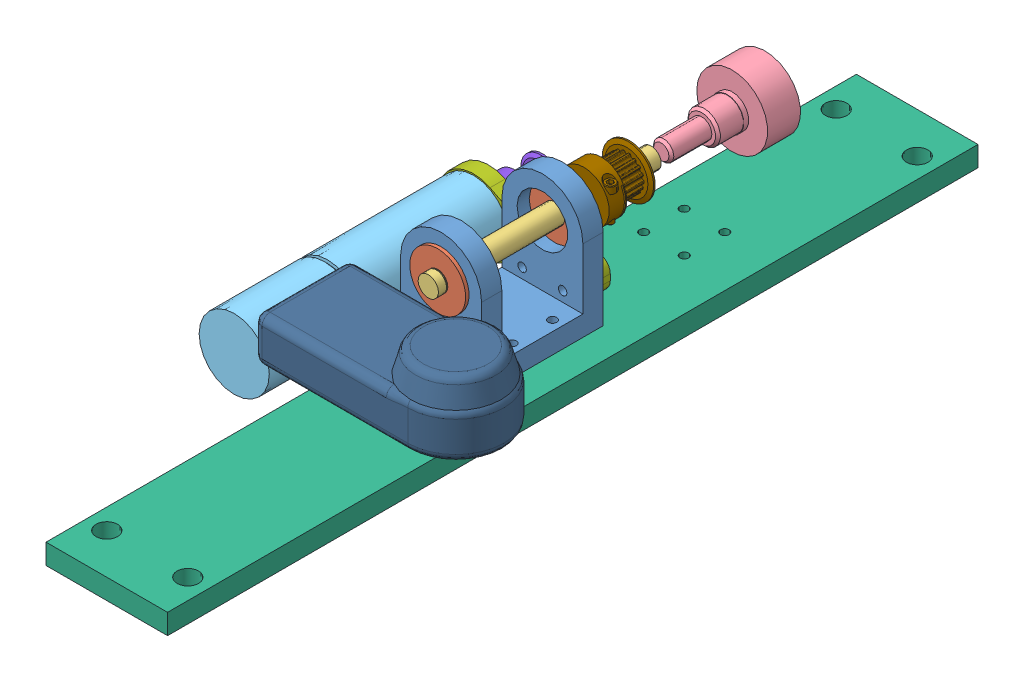
SolidWorks assembly NECK_YOKE_ASM, configuration Default. Lengths in mm.
Overall size (86.8 44.45 254).
11 component instances, 10 part files, 25 mates.
Components (placement in the parent):
- n01-yoke-1: n01-yoke [Default] at origin size (28.53 38.1 38.1)
- 000_rb-p25xp625-57155K324mcm-1: 000_rb-p25xp625-57155K324mcm [Default] at (0 25.4 -16.51) x (0 0 1) z (-0.947787 -0.318905 0) size (3.61 17.53 17.53)
- 000_rb-p25xp625-57155K324mcm-2: 000_rb-p25xp625-57155K324mcm [Default] at (0 25.4 16.51) x (0 0 -1) z (0.870377 -0.492386 0) size (3.61 17.53 17.53)
- n02-neck-pitch-shaft-1: n02-neck-pitch-shaft [Default] at (0 25.4 -11.8618) x (0.984383 -0.176038 0) z (0 0 1) size (6.34 6.34 69.85)
- bourns-6639-1: bourns-6639 [Default] at (0 25.4 -82.4992) x (0 0 -1) z (0.999946 -0.010393 0) size (35.71 22.23 22.23)
- MAXON-amax22-n-gear143991-1: MAXON-amax22-n-gear143991 [Default] at (-27.94 9.525 26.75) x (0 0 1) z (-1 0 0) size (89.5 22 22)
- n03-neck-baseplate-to-body-1: n03-neck-baseplate-to-body [Default] at (3.175 0 0) x (0 0 -1) z (0 -1 0) size (254 38.1 6.35)
- n04-motor-mount-1: n04-motor-mount [Default] at (-27.94 9.525 -19.05) x (-1 0 0) z (0 0 -1) size (49.53 22.86 4.76)
- a_6d16m012df6003-3mm-bored-to-4mm-1: a_6d16m012df6003-3mm-bored-to-4mm [Default] at (-27.94 9.525 -32.3525) size (12.2 12.2 14.3)
- a_6d16-018df2508-2: a_6d16-018df2508 [Default] at (0 25.4 -31.6681) x (0.999994 -0.003333 0) z (0 0 1) size (16.13 16.13 14.29)
- LOGITECH_USB_CAM-1: LOGITECH_USB_CAM [Default] at (32.385 15.875 46.7995) x (0 0 -1) z (0 1 0) size (30.1 63.31 29.21)
Mates (geometry in assembly coordinates):
- Coincident1: coincident anti-aligned: plane of n01-yoke-1 through (0 25.4 -19.05) normal (0 0 -1); plane of 000_rb-p25xp625-57155K324mcm-1 through (8.3055 28.1946 -19.05) normal (0 0 1)
- Coincident2: coincident anti-aligned: plane of n01-yoke-1 through (0 25.4 19.05) normal (0 0 1); plane of 000_rb-p25xp625-57155K324mcm-2 through (-7.6271 29.7148 19.05) normal (0 0 -1)
- Concentric1: concentric aligned: cylinder of n01-yoke-1; cylinder of 000_rb-p25xp625-57155K324mcm-2
- Concentric2: concentric anti-aligned: cylinder of n01-yoke-1; cylinder of 000_rb-p25xp625-57155K324mcm-1
- Concentric3: concentric anti-aligned: cylinder of 000_rb-p25xp625-57155K324mcm-1; cylinder of n02-neck-pitch-shaft-1
- Concentric4: concentric aligned: cylinder of n02-neck-pitch-shaft-1; cylinder of bourns-6639-1
- Coincident6: coincident anti-aligned: plane of n01-yoke-1 through (12.7 0 19.05) normal (0 -1 0); plane of n03-neck-baseplate-to-body-1 through (-15.875 0 127) normal (0 1 0)
- Coincident7: coincident anti-aligned: plane of n01-yoke-1 through (0 0 0) normal (0 0 1); plane of n03-neck-baseplate-to-body-1 through (3.175 0 0) normal (0 0 -1)
- Coincident8: coincident anti-aligned: plane of n01-yoke-1 through (0 0 0) normal (0 1 0); plane of n03-neck-baseplate-to-body-1 through (3.175 0 0) normal (0 -1 0)
- Coincident11: coincident aligned: plane of MAXON-amax22-n-gear143991-1 through (-22.94 9.525 -19.05) normal (0 0 -1); plane of n01-yoke-1 through (0 25.4 -19.05) normal (0 0 -1)
- Concentric6: concentric aligned: cylinder of MAXON-amax22-n-gear143991-1; cylinder of n04-motor-mount-1
- Concentric7: concentric aligned: cylinder of MAXON-amax22-n-gear143991-1; cylinder of n04-motor-mount-1
- Coincident12: coincident anti-aligned: plane of MAXON-amax22-n-gear143991-1 through (-22.94 9.525 -19.05) normal (0 0 -1); plane of n04-motor-mount-1 through (-27.94 9.525 -19.05) normal (0 0 1)
- Parallel2: parallel aligned: plane of n03-neck-baseplate-to-body-1 through (-15.875 0 127) normal (0 1 0); plane of n04-motor-mount-1 through (-12.065 14.2875 -23.8125) normal (0 1 0)
- Concentric8: concentric aligned: cylinder of n01-yoke-1; cylinder of n04-motor-mount-1
- Concentric9: concentric anti-aligned: cylinder of n01-yoke-1; cylinder of n03-neck-baseplate-to-body-1
- Coincident15: coincident aligned: plane of 000_rb-p25xp625-57155K324mcm-1 through (3.0092 26.4125 -20.1168) normal (0 0 -1); plane of n02-neck-pitch-shaft-1 through (29.287 20.1626 -20.1168) normal (0 0 -1)
- Distance3: distance = 3.175 mm anti-aligned: plane of n02-neck-pitch-shaft-1 through (0 25.4 -46.7868) normal (0 0 -1); plane of bourns-6639-1 through (0.033 28.5748 -49.9618) normal (0 0 1)
- Concentric10: concentric anti-aligned: cylinder of n02-neck-pitch-shaft-1; cylinder of a_6d16-018df2508-2
- Distance4: distance = 2.54 mm anti-aligned: plane of n04-motor-mount-1 through (-27.94 9.525 -23.8125) normal (0 0 -1); plane of a_6d16m012df6003-3mm-bored-to-4mm-1 through (-27.94 15.625 -26.3525) normal (0 0 1)
- Concentric12: concentric aligned: cylinder of MAXON-amax22-n-gear143991-1; cylinder of a_6d16m012df6003-3mm-bored-to-4mm-1
- Coincident19: coincident aligned: plane of a_6d16m012df6003-3mm-bored-to-4mm-1 through (-27.94 14.4992 -40.0025) normal (0 0 -1); plane of a_6d16-018df2508-2 through (0 25.4 -40.0025) normal (0 0 -1)
- Coincident20: coincident aligned: plane of n03-neck-baseplate-to-body-1 through (-15.875 -6.35 127) normal (-1 0 0); plane of LOGITECH_USB_CAM-1 through (-15.875 29.845 61.849) normal (-1 0 0)
- Distance5: distance = 12.7 mm anti-aligned: plane of n01-yoke-1 through (0 25.4 19.05) normal (0 0 1); plane of LOGITECH_USB_CAM-1 through (32.385 29.845 31.75) normal (0 0 -1)
- Distance6: distance = 15.875 mm anti-aligned: plane of n03-neck-baseplate-to-body-1 through (-15.875 0 127) normal (0 1 0); plane of LOGITECH_USB_CAM-1 through (32.385 15.875 46.7995) normal (0 -1 0)
